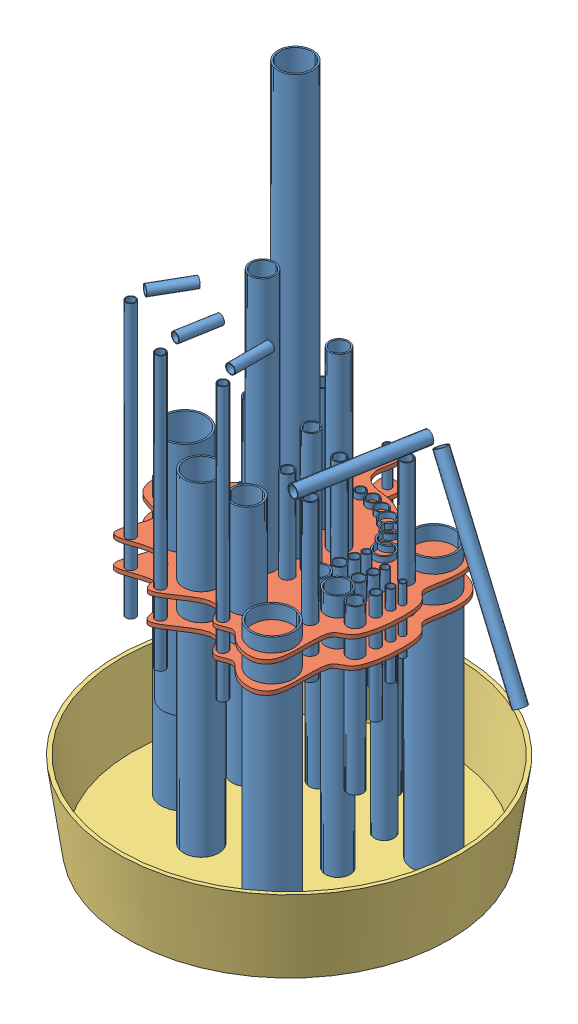
SolidWorks assembly bouwplan versie 2, configuration Default. Lengths in mm.
Overall size (974.79 1754.47 880).
64 component instances, 3 part files, 2 mates.
Components (placement in the parent):
- Center^bouwplan versie 2-1: Center^bouwplan versie 2 [Default] at (-139.7323 -488.9261 40.3197) size (225.58 1262.05 223.38) (virtual)
  - PVC buis-1: PVC buis [center1] at (88.227 0 -37.3541) x (0.959163 0 0.282853) z (-0.282853 0 0.959163) size (90 1262.05 90)
  - PVC buis-2: PVC buis [center2] at (88.8656 0 47.4581) size (63 841.86 63)
  - PVC buis-3: PVC buis [center3] at (147.3385 0 -90.0112) size (50 630.2 50)
  - PVC buis-4: PVC buis [center4] at (19.6485 0 -75.7212) size (50 630.2 50)
  - PVC buis-5: PVC buis [center5] at (160.7286 0 -5.3135) size (40 500.11 40)
  - PVC buis-6: PVC buis [center6] at (75.6711 0 -120.0958) size (40 500.11 40)
  - PVC buis-7: PVC buis [center7] at (15.6572 0 0.0843) size (40 500.11 40)
  - PVC buis-8: PVC buis [center8] at (145.6349 0 40.5402) size (32 421.16 32)
  - PVC buis-9: PVC buis [center9] at (184.3537 0 -54.1519) size (32 421.16 32)
  - PVC buis-10: PVC buis [center10] at (119.6942 0 -128.4252) size (32 421.16 32)
  - PVC buis-11: PVC buis [center11] at (35.6941 0 -122.4712) size (25 315.13 25)
  - PVC buis-12: PVC buis [center12] at (-12.7254 0 -37.9209) size (25 315.13 25)
  - PVC buis-13: PVC buis [center13] at (30.6398 0 44.1326) size (25 315.13 25)
- drum^bouwplan versie 2-1: drum^bouwplan versie 2 [Default] at (428.3985 -61.3694 126.1072) size (349.63 1154.45 211.69) (virtual)
  - PVC buis-1: PVC buis [drum1] at (-411.135 -619.4374 70.4886) size (75 619.44 75)
  - PVC buis-3: PVC buis [drum2] at (-527.6846 -829.9029 70.437) size (90 829.9 90)
  - PVC buis-4: PVC buis [drum3] at (-642.282 -603.1534 -2.0664) size (110 603.15 110)
  - PVC buis-5: PVC buis [drumLong] at (-710.7627 -416.7688 68.1435) size (25 700 25)
  - PVC buis-8: PVC buis [drumLong] at (-560.6027 -420.5761 142.1194) size (25 700 25)
  - PVC buis-9: PVC buis [drumLong] at (-408.8428 -417.2511 133.6251) size (25 700 25)
  - PVC buis-10: PVC buis [drumTransparent] at (-634.8078 312.0472 -29.456) x (0.866025 0 0.5) z (0 -1 0) size (25 100 25)
  - PVC buis-11: PVC buis [drumTransparent] at (-527.5243 308.367 21.2821) x (0.984808 0 0.173648) z (0 -1 0) size (25 100 25)
  - PVC buis-12: PVC buis [drumTransparent] at (-414.1268 298.3703 9.026) x (1 0 0) z (0 -1 0) size (25 100 25)
- chords^bouwplan versie 2-1: chords^bouwplan versie 2 [Default] at (237.1797 -253.4683 198.1208) x (0.173648 0 -0.984808) z (-0.984808 0 -0.173648) size (333.17 895.74 372.51) (virtual)
  - PVC buis-1: PVC buis [chordC1] at (90.9992 0 111.1061) size (63 624.31 63)
  - PVC buis-2: PVC buis [chordC2] at (136.3076 0 111.1061) size (32 312.37 32)
  - PVC buis-3: PVC buis [chordC3] at (169.3713 0 111.1061) size (25 248.11 25)
  - PVC buis-4: PVC buis [chordC4] at (195.7171 0 111.1061) size (20 209.02 20)
  - PVC buis-5: PVC buis [chordF1] at (90.9992 0 170.8789) size (50 467.2 50)
  - PVC buis-6: PVC buis [chordF2] at (136.3076 0 170.8789) size (32 312.37 32)
  - PVC buis-7: PVC buis [chordF3] at (169.3713 0 170.8789) size (25 233.64 25)
  - PVC buis-8: PVC buis [chordF4] at (195.7171 0 170.8789) size (20 185.36 20)
  - PVC buis-9: PVC buis [chordG1] at (90.9992 0 56.2975) size (40 418.03 40)
  - PVC buis-10: PVC buis [chordG2] at (136.3076 0 56.2975) size (25 279.7 25)
  - PVC buis-11: PVC buis [chordG3] at (169.3713 0 56.2975) size (20 209.02 20)
  - PVC buis-12: PVC buis [chordG4] at (195.7171 0 56.2975) size (16 166.13 16)
  - PVC buis-14: PVC buis [chordStaanders] at (27.5057 175.1312 108.0542) x (0.984808 0 0.173648) z (0.173648 0 -0.984808) size (32 400 32)
  - PVC buis-15: PVC buis [chordStaanders] at (242.0118 175.6387 109.7217) x (0.984808 0 0.173648) z (0.173648 0 -0.984808) size (32 400 32)
  - PVC buis-16: PVC buis [chordHandle] at (304.1804 197.457 -160.5823) x (0.984808 0.086824 0.150384) z (0.173648 -0.492404 -0.852869) size (32 500 32)
  - PVC buis-17: PVC buis [chordSprayTransparent] at (-10.4528 -252.8879 107.5679) x (0 0.984808 0.173648) z (0 0.173648 -0.984808) size (32 300 32)
- melody^bouwplan versie 2-1: melody^bouwplan versie 2 [Default] at (-113.1843 -445.7497 20.3897) x (-0.766044 0 0.642788) z (0.642788 0 0.766044) size (346.91 640.7 357.98) (virtual)
  - PVC buis-1: PVC buis [melody1] at (78.8472 -157.8462 -114.2726) size (12 157.85 12)
  - PVC buis-2: PVC buis [melody2] at (54.6207 -157.8462 -137.3285) x (0.981627 0 -0.190809) z (0.190809 0 0.981627) size (12 167.51 12)
  - PVC buis-3: PVC buis [melody3] at (26.4401 -157.8462 -155.3381) x (0.927184 0 -0.374607) z (0.374607 0 0.927184) size (16 187.2 16)
  - PVC buis-4: PVC buis [melody4] at (-4.6591 -157.8462 -167.6398) x (0.838671 0 -0.544639) z (0.544639 0 0.838671) size (16 210.86 16)
  - PVC buis-5: PVC buis [melody5] at (-37.5342 -157.8462 -173.7814) x (0.71934 0 -0.694658) z (0.694658 0 0.71934) size (20 235.57 20)
  - PVC buis-6: PVC buis [melody6] at (-70.9772 -157.8462 -173.5373) x (0.573576 0 -0.819152) z (0.819152 0 0.573576) size (20 250.04 20)
  - PVC buis-7: PVC buis [melody7] at (-103.7591 -157.8462 -166.9164) x (0.406737 0 -0.913545) z (0.913545 0 0.406737) size (25 279.7 25)
  - PVC buis-8: PVC buis [melody8] at (-134.6755 -157.8462 -154.1621) x (0.224951 0 -0.97437) z (0.97437 0 0.224951) size (25 315.13 25)
  - PVC buis-9: PVC buis [melody9] at (-162.5902 -157.8462 -135.7431) x (0.034899 0 -0.999391) z (0.999391 0 0.034899) size (25 334.46 25)
  - PVC buis-10: PVC buis [melody10] at (-186.4775 -157.8462 -112.336) x (-0.156434 0 -0.987688) z (0.987688 0 -0.156434) size (32 373.85 32)
  - PVC buis-11: PVC buis [melody11] at (-205.4597 -157.8462 -84.8011) x (-0.34202 0 -0.939693) z (0.939693 0 -0.34202) size (32 421.16 32)
  - PVC buis-12: PVC buis [melody12] at (-218.8391 -157.8462 -54.1502) x (-0.515038 0 -0.857167) z (0.857167 0 -0.515038) size (40 471.16 40)
  - PVC buis-13: PVC buis [melody13] at (-226.1243 -157.8462 -21.5094) x (-0.669131 0 -0.743145) z (0.743145 0 -0.669131) size (40 500.11 40)
  - PVC buis-14: PVC buis [melody14] at (-227.0475 -157.8462 11.9217) x (-0.798636 0 -0.601815) z (0.601815 0 -0.798636) size (50 559.3 50)
  - PVC buis-15: PVC buis [melody15] at (-221.5748 -157.8462 44.9148) x (-0.898794 0 -0.438371) z (0.438371 0 -0.898794) size (50 630.2 50)
  - PVC buis-16: PVC buis [melodySupply] at (-200.3229 -168.3435 -266.4332) x (0.406737 0 -0.913545) z (0.913545 0 0.406737) size (20 200 20)
- Board ^bouwplan versie 2-1: Board ^bouwplan versie 2 [Default] at (-0.3435 -312.0405 0.0811) x (1 0 0) z (0 1 0) size (644.73 673.07 10) (virtual)
- Board ^bouwplan versie 2-2: Board ^bouwplan versie 2 [Default] at (0.3468 -380.6074 1.2232) x (1 0 0) z (0 1 0) size (644.73 673.07 10) (virtual)
- PVC buis-17: PVC buis [paal] at (-308.4098 -966.6074 35.0291) size (110 700 110)
- PVC buis-18: PVC buis [paal] at (152.8124 -966.6074 -147.4839) size (110 700 110)
- PVC buis-19: PVC buis [paal] at (120.5633 -966.6074 234.7359) size (110 700 110)
- Part2^bouwplan versie 2-3: Part2^bouwplan versie 2 [different] at (-16.1179 -776.3464 0) x (1 0 0) z (0 1 0) size (880 880 205) (virtual)
Mates (geometry in assembly coordinates):
- Coincident3: coincident aligned: plane of PVC buis-17 through (-308.4098 -266.6074 35.0291) normal (0 1 0); plane of PVC buis-18 through (152.8124 -266.6074 -147.4839) normal (0 1 0)
- Coincident4: coincident aligned: plane of PVC buis-17 through (-308.4098 -266.6074 35.0291) normal (0 1 0); plane of PVC buis-19 through (120.5633 -266.6074 234.7359) normal (0 1 0)
